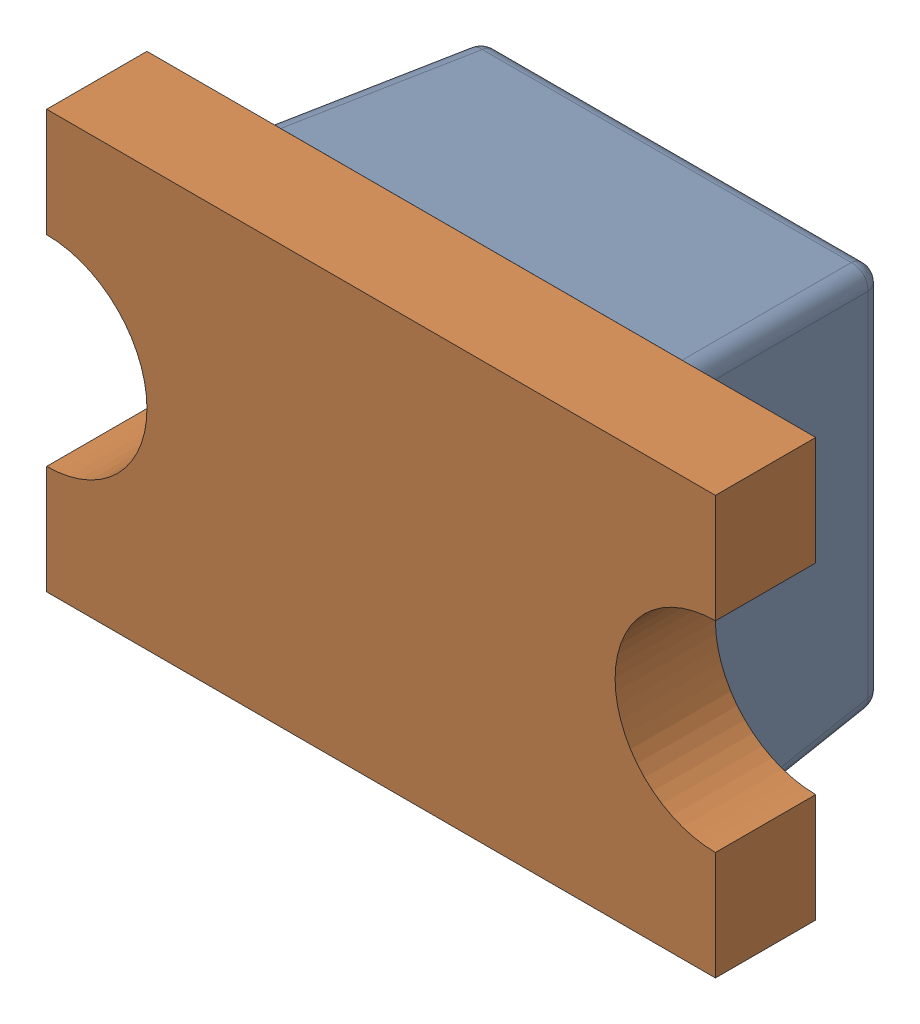
SolidWorks assembly D8_3, configuration Default. Lengths in mm.
Overall size (2 1.25 0.9).
2 component instances, 2 part files, 0 mates.
Components (placement in the parent):
- LED 0805 Lens RED-1: LED 0805 Lens RED [Default] at (140.8309 95.631 -1.2114) x (-1 0 0) z (0 -1 0) size (1.3 0.6 1.25)
- LED 0805 Base RED-1: LED 0805 Base RED [Default] at (140.8309 95.631 -1.2114) x (-1 0 0) z (0 -1 0) size (2 0.4 1.25)
